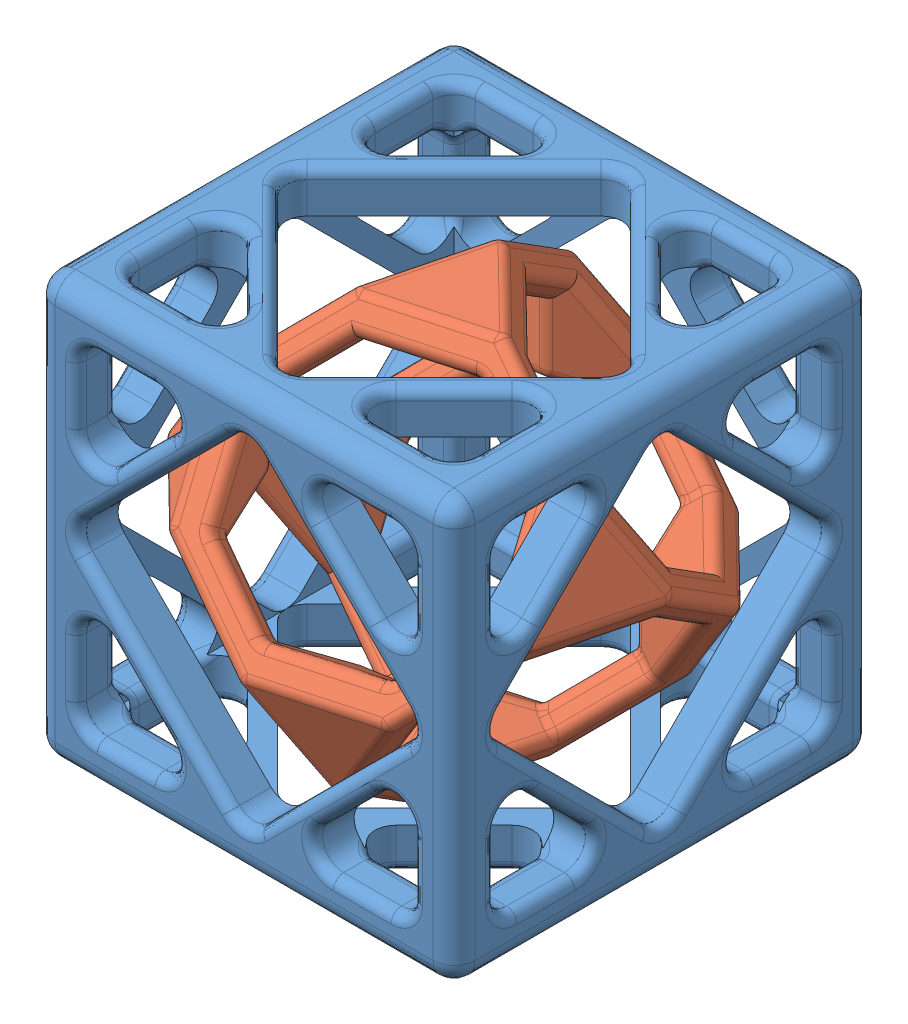
SolidWorks assembly Assem1, configuration Default. Lengths in mm.
Overall size (44.29 48.5 44.04).
2 component instances, 2 part files, 3 mates.
Components (placement in the parent):
- Part1-1: Part1 [Default] at origin size (40 40 40)
- Part2-1: Part2 [Default] at (0 19.2487 0) x (-0.571178 -0.57735 0.583458) z (-0.790878 0.57735 -0.202925) size (28 28 28)
Mates (geometry in assembly coordinates):
- Coincident1: coordinate: point of Part1-1
- Coincident2: coincident anti-aligned: plane of Part2-1 through (0 0 0) normal (0 -1 0)
- Coincident3: coincident aligned: line of Part1-1 through (44 0 42) axis (0 0 -1); line of Part2-1 through (48.4974 0 43.4974) axis (0 0 -1)
